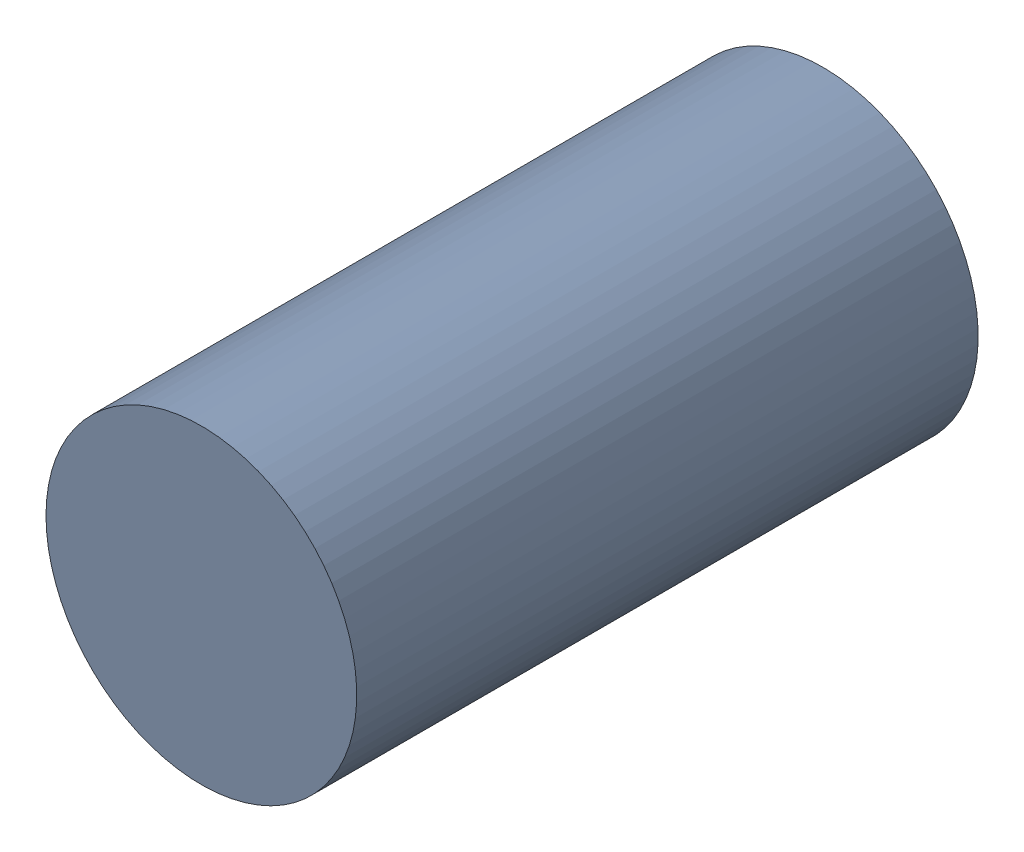
SolidWorks assembly MH10_2.step, configuration Default. Lengths in mm.
Overall size (1 1 2).
2 component instances, 1 part files, 0 mates.
Components (placement in the parent):
- 11929539264.step-1: 11929539264.step [Default] at (59.1743 54.2886 -1.5) x (-1 0 0) z (0 0 1) size (1 1 2)
  - Cylinder_2.step-7: Cylinder_2.step [Default] at origin size (1 1 2)
